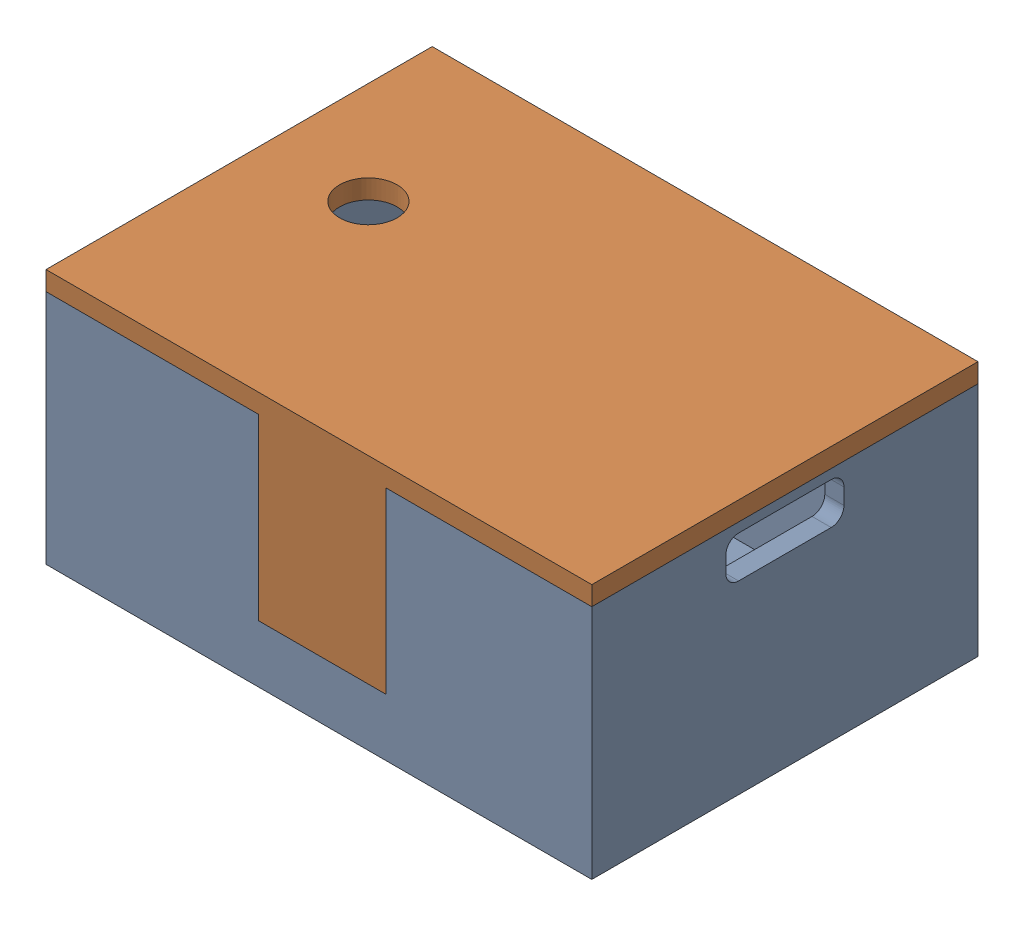
SolidWorks assembly full, configuration Default. Lengths in mm.
Overall size (42.75 20 30.25).
2 component instances, 2 part files, 3 mates.
Components (placement in the parent):
- case-1: case [Default] at (-37.8683 14.3917 60.4441) size (42.75 18.5 30.25)
- cover-1: cover [Default] at (-38.1183 32.8917 60.4441) x (1 0 0) z (0 1 0) size (42.75 30.25 15.5)
Mates (geometry in assembly coordinates):
- Coincident1: coincident anti-aligned: plane of case-1 through (-37.8683 32.8917 60.4441) normal (0 1 0); plane of cover-1 through (-38.1183 32.8917 60.4441) normal (0 -1 0)
- Coincident2: coincident aligned: plane of case-1 through (-16.7433 102.2618 45.3191) normal (1 0 0); plane of cover-1 through (-16.7433 34.3917 75.5691) normal (1 0 0)
- Coincident3: coincident aligned: plane of case-1 through (-16.7433 102.2618 75.5691) normal (0 0 1); plane of cover-1 through (-59.4933 34.3917 75.5691) normal (0 0 1)
